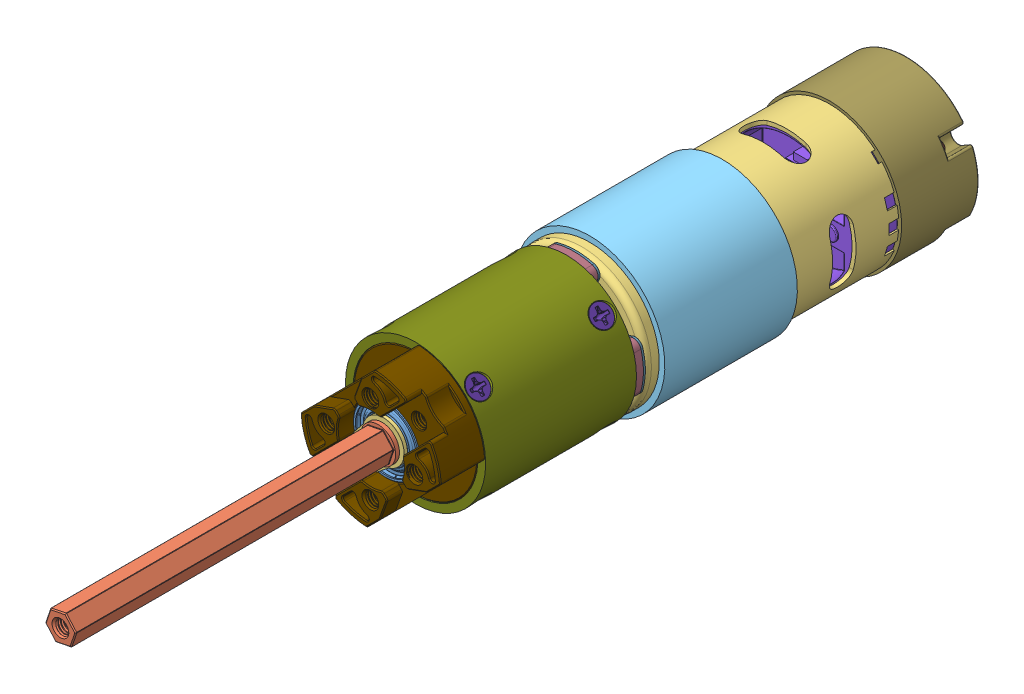
SolidWorks assembly 5304-8002-0051, configuration Default. Lengths in mm.
Overall size (50.88 50.88 217.25).
47 component instances, 22 part files, 0 mates.
Components (placement in the parent):
- 5304-8002-0051.step-1: 5304-8002-0051.step [Default] at origin size (50.88 50.88 217.25)
  - 5001-0002-0001.step-1: 5001-0002-0001.step [Default] x (-1 0 0) z (0 0 1) size (38.5 38.5 98.95)
    - MainBody.step-1: MainBody.step [Default] at origin size (38.5 38.5 81)
      - Bearing.step-1: Bearing.step [Default] at origin size (11 11 4)
        - OD.step-1: OD.step [Default] at origin
        - IR.step-1: IR.step [Default] at origin
      - Casing.step-1: Casing.step [Default] at origin
      - Core.step-1: Core.step [Default] at origin
      - Ring.step-1: Ring.step [Default] at origin
      - Fan.step-1: Fan.step [Default] at origin
      - Magnets.step-1: Magnets.step [Default] at origin
      - Cap.step-1: Cap.step [Default] at origin
    - EncoderCap.step-1: EncoderCap.step [Default] at origin size (37 37 19.95)
      - JST-XH-4POS-VERT.step-1: JST-XH-4POS-VERT.step [Default] at (2.8 12.25 -75.95) x (1 0 0) z (0 0 -1) size (12.4 5.75 10.4)
        - Plastic.step-1: Plastic.step [Default] at (0 -2.875 0)
        - Pin.step-1: Pin.step [Default] at (3.75 -0.525 1.6)
        - Pin.step-2: Pin.step [Default] at (-3.75 -0.525 1.6)
        - Pin.step-3: Pin.step [Default] at (-1.25 -0.525 1.6)
        - Pin.step-4: Pin.step [Default] at (1.25 -0.525 1.6)
      - CapScrew.step-1: CapScrew.step [Default] at (-41.264 -8.1646 3.9905) x (0.882398 0 0.470504) z (0 -1 0) size (6.57 8.18 3.5)
        - 99461A915_Phillips Rounded Head Thread-Forming Screws.step-1: 99461A915_Phillips Rounded Head Thread-Forming Screws.step [Default] at (-16.3394 -89.8152 -0.4146) x (0.882398 -0.470504 0) z (-0.470504 -0.882398 0)
      - CapScrew.step-2: CapScrew.step [Default] at (-14.4172 7.3354 3.9905) x (0.882398 0 0.470504) z (0 -1 0) size (6.57 8.18 3.5)
        - 99461A915_Phillips Rounded Head Thread-Forming Screws.step-1: 99461A915_Phillips Rounded Head Thread-Forming Screws.step [Default] at (-16.3394 -89.8152 -0.4146) x (0.882398 -0.470504 0) z (-0.470504 -0.882398 0)
      - Endcap.step-1: Endcap.step [Default] at origin
    - Spacers.step-1: Spacers.step [Default] at origin size (35.5 35.5 2.5)
      - PCB.step-1: PCB.step [Default] at (-11.099 -71.9658 -4)
      - Steel.step-1: Steel.step [Default] at (-11.099 -71.9658 -4.5)
  - 5104-0080-0051.step-1: 5104-0080-0051.step [Default] at origin size (50.88 50.88 135.68)
    - 5103 Gearbox Base.step-1: 5103 Gearbox Base.step [Default] at (0 0 -2) x (-0.707107 -0.707107 0) z (-0.707107 0.707107 0)
    - 5103 Gearbox Barrel (3 stage, simple)_Gear Blank.step-1: 5103 Gearbox Barrel (3 stage, simple)_Gear Blank.step [Default] at (0 0 49.7) x (-0.707107 -0.707107 0) z (0 0 -1)
    - 5103 Gearbox Barrel Screw (M3 x 8mm length Flat Head)_92010A118.step-1: 5103 Gearbox Barrel Screw (M3 x 8mm length Flat Head)_92010A118.step [Default] at (-11.3724 11.3724 1.5) x (-0.001725 -0.001725 -0.999997) z (-0.707107 0.707107 0)
    - 5103 Gearbox Face.step-1: 5103 Gearbox Face.step [Default] at (0 0 31.2) x (-0.707107 -0.707107 0) z (-0.707107 0.707107 0)
    - 5103 Gearbox Bearing.step-1: 5103 Gearbox Bearing.step [Default] at (0 0 39.3) x (-0.707107 -0.707107 0) z (-0.707107 0.707107 0)
    - 5103 Gearbox Shaft (79.5mm Length, Simple).step-1: 5103 Gearbox Shaft (79.5mm Length, Simple).step [Default] at (0 0 27.84) x (-0.316963 -0.948438 0) z (-0.948438 0.316963 0)
    - 5103 Gearbox Snap Ring.step-1: 5103 Gearbox Snap Ring.step [Default] at (0 0 44.375) x (0 0 1) z (-0.707107 0.707107 0)
    - 5103 Gearbox Base Mounting Screw M3 x 8mm length SHCS)_91290A113.step-1: 5103 Gearbox Base Mounting Screw M3 x 8mm length SHCS)_91290A113.step [Default] at (12.5 0 -2.38) x (0.707107 0.707107 0) z (0 0 1)
    - 5103 Gearbox Barrel Screw (M3 x 8mm length Flat Head)_92010A118.step-2: 5103 Gearbox Barrel Screw (M3 x 8mm length Flat Head)_92010A118.step [Default] at (-11.3724 11.3724 33.2) x (0.001725 0.001725 -0.999997) z (-0.707107 0.707107 0)
    - 5103 Gearbox Barrel Screw (M3 x 8mm length Flat Head)_92010A118.step-3: 5103 Gearbox Barrel Screw (M3 x 8mm length Flat Head)_92010A118.step [Default] at (-11.3724 -11.3724 1.5) x (0.001725 -0.001725 -0.999997) z (-0.707107 -0.707107 0)
    - 5103 Gearbox Barrel Screw (M3 x 8mm length Flat Head)_92010A118.step-4: 5103 Gearbox Barrel Screw (M3 x 8mm length Flat Head)_92010A118.step [Default] at (11.3724 -11.3724 1.5) x (0.001725 0.001725 -0.999997) z (0.707107 -0.707107 0)
    - 5103 Gearbox Barrel Screw (M3 x 8mm length Flat Head)_92010A118.step-5: 5103 Gearbox Barrel Screw (M3 x 8mm length Flat Head)_92010A118.step [Default] at (11.3724 11.3724 1.5) x (-0.001725 0.001725 -0.999997) z (0.707107 0.707107 0)
    - 5103 Gearbox Barrel Screw (M3 x 8mm length Flat Head)_92010A118.step-6: 5103 Gearbox Barrel Screw (M3 x 8mm length Flat Head)_92010A118.step [Default] at (-11.3724 -11.3724 33.2) x (-0.001725 0.001725 -0.999997) z (-0.707107 -0.707107 0)
    - 5103 Gearbox Barrel Screw (M3 x 8mm length Flat Head)_92010A118.step-7: 5103 Gearbox Barrel Screw (M3 x 8mm length Flat Head)_92010A118.step [Default] at (11.3724 -11.3724 33.2) x (-0.001725 -0.001725 -0.999997) z (0.707107 -0.707107 0)
    - 5103 Gearbox Barrel Screw (M3 x 8mm length Flat Head)_92010A118.step-8: 5103 Gearbox Barrel Screw (M3 x 8mm length Flat Head)_92010A118.step [Default] at (11.3724 11.3724 33.2) x (0.001725 -0.001725 -0.999997) z (0.707107 0.707107 0)
    - 5103 Gearbox Bearing.step-2: 5103 Gearbox Bearing.step [Default] at (0 0 31.2) x (-0.707107 -0.707107 0) z (-0.707107 0.707107 0)
    - 5103 Gearbox Base Mounting Screw M3 x 8mm length SHCS)_91290A113.step-2: 5103 Gearbox Base Mounting Screw M3 x 8mm length SHCS)_91290A113.step [Default] at (0 -12.5 -2.38) x (0.707107 0.707107 0) z (0 0 1)
    - 5103 Gearbox Base Mounting Screw M3 x 8mm length SHCS)_91290A113.step-3: 5103 Gearbox Base Mounting Screw M3 x 8mm length SHCS)_91290A113.step [Default] at (0 12.5 -2.38) x (0.707107 0.707107 0) z (0 0 1)
    - 5103 Gearbox Base Mounting Screw M3 x 8mm length SHCS)_91290A113.step-4: 5103 Gearbox Base Mounting Screw M3 x 8mm length SHCS)_91290A113.step [Default] at (-12.5 0 -2.38) x (0.707107 0.707107 0) z (0 0 1)
